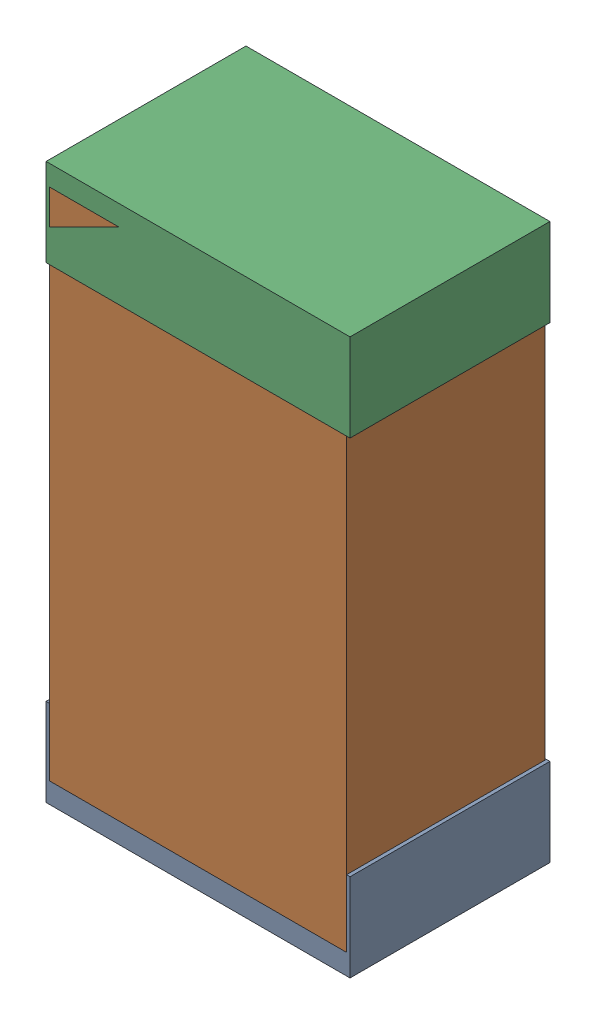
SolidWorks assembly R43Kanaloa_v2.0.0_Motor, configuration Default. Lengths in mm.
Overall size (1.3 2.38 0.85).
6 component instances, 2 part files, 0 mates.
Components (placement in the parent):
- 330415056-1: 330415056 [Default] at (127 118.634 -1.9574) size (1.3 0.38 0.85)
  - Extruded_2-1: Extruded_2 [Default] at origin size (1.3 0.38 0.85)
- 334787376-1: 334787376 [Default] at (127 119.634 -1.9524) size (1.27 2.2 0.85)
  - Extruded_16-1: Extruded_16 [Default] at origin size (1.27 2.2 0.85)
- 330415056-2: 330415056 [Default] at (127 120.634 -1.9574) size (1.3 0.38 0.85)
  - Extruded_2-1: Extruded_2 [Default] at origin size (1.3 0.38 0.85)
